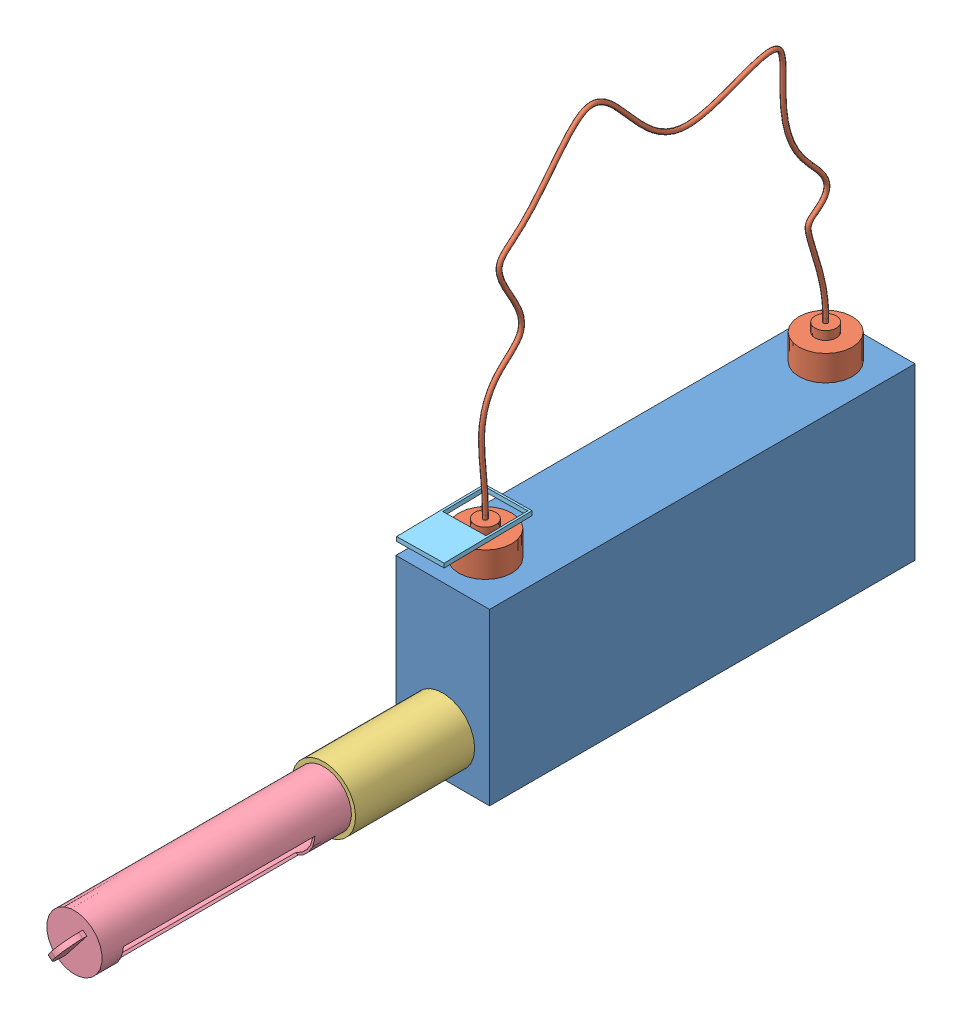
SolidWorks assembly lec44-path-mate-linear-coupler, configuration Default. Lengths in mm.
Overall size (55.88 307.6 486.58).
5 component instances, 5 part files, 22 mates.
Components (placement in the parent):
- Main Part_Path Mate-1: Main Part_Path Mate [Default] at (91.5285 149.8343 184.9571) size (55.88 101.6 254)
- Copy of Copy of Copy of Part3^lec44-path-mate-linear-coupler-1: Copy of Copy of Copy of Part3^lec44-path-mate-linear-coupler [Default] at (91.5285 200.6343 184.9571) x (1 0 0) z (0 1 0) size (31.75 234.95 254.26) (virtual)
- Part4^lec44-path-mate-linear-coupler-1: Part4^lec44-path-mate-linear-coupler [Default] at (67.487 132.6298 383.0215) x (0.322658 0.946515 0) z (0 0 1) size (38.1 38.1 228.6) (virtual)
- drawer_2-1: drawer_2 [Default] at (111.5159 108.7607 519.1401) x (-0.617072 -0.786907 0) z (0 0 1) size (33.02 33.02 241.3)
- Ring_2-1: Ring_2 [Default] at (91.5285 223.4943 286.5571) x (0.999879 0 -0.015556) z (0 1 0) size (27.94 53.34 2.54)
Mates (geometry in assembly coordinates):
- InPlace1: in place: plane of Main Part_Path Mate-1 through (123.2785 200.6343 57.9571) normal (0 1 0); plane of ? through (0 200.6343 0) normal (0 1 0); moOrthogonalPlaneRef_w of Main Part_Path Mate-1 through (123.2785 200.6343 57.9571) normal (0 1 0); plane of ? through (0 200.6343 0) normal (0 0 -1); plane of Main Part_Path Mate-1 through (123.2785 200.6343 57.9571) normal (0 1 0); line of ? through (-55 0 200.6343) axis (0 1 0); plane of Main Part_Path Mate-1 through (119.4685 200.6343 57.9571) normal (0 1 0); unknown of Copy of Copy of Copy of Part3^lec44-path-mate-linear-coupler-1
- Coincident1: coincident aligned: plane of ?; plane of ?
- Coincident2: coincident aligned: moOrthogonalPlaneRef_w of Main Part_Path Mate-1 through (91.5285 200.6343 184.9571) normal (0 0 -1); plane of Copy of Copy of Copy of Part3^lec36-path-mate-linear-coupler-1 through (91.5285 200.6343 184.9571) normal (0 0 -1)
- Coincident3: coincident anti-aligned: moOrthogonalPlaneRef_w of Main Part_Path Mate-1 through (91.5285 200.6343 184.9571) normal (-1 0 0); plane of Copy of Copy of Copy of Part3^lec36-path-mate-linear-coupler-1 through (91.5285 200.6343 184.9571) normal (1 0 0)
- InPlace2: in place: plane of Main Part_Path Mate-1 through (123.2785 200.6343 311.9571) normal (0 0 1); plane of ? through (0 0 311.9571) normal (0 0 1); plane of Main Part_Path Mate-1 through (123.2785 200.6343 311.9571) normal (0 0 1); plane of ? through (0 0 311.9571) normal (0 1 0); plane of Main Part_Path Mate-1 through (123.2785 200.6343 311.9571) normal (0 0 1); plane of ? through (0 0 311.9571) normal (1 0 0); plane of Main Part_Path Mate-1 through (119.4685 200.6343 311.9571) normal (0 0 1); unknown of ?
- Coincident1: coincident: plane of ?; plane of ?
- Coincident2: coincident aligned: moOrthogonalPlaneRef_w of Main Part_Path Mate-1 through (91.5285 149.8343 311.9571) normal (0 1 0); plane of Part4^lec36-path-mate-linear-coupler-1
- Coincident3: coincident anti-aligned: moOrthogonalPlaneRef_w of Main Part_Path Mate-1 through (91.5285 149.8343 311.9571) normal (-1 0 0); plane of Part4^lec36-path-mate-linear-coupler-1
- InPlace3: in place: plane of Main Part_Path Mate-1 through (123.2785 200.6343 311.9571) normal (0 0 1); plane of ? through (0 0 311.9571) normal (0 0 1); plane of Main Part_Path Mate-1 through (123.2785 200.6343 311.9571) normal (0 0 1); plane of ? through (0 0 311.9571) normal (0 1 0); plane of Main Part_Path Mate-1 through (123.2785 200.6343 311.9571) normal (0 0 1); plane of ? through (0 0 311.9571) normal (1 0 0); plane of Main Part_Path Mate-1 through (119.4685 200.6343 311.9571) normal (0 0 1); unknown of ?
- Coincident4: coincident: plane of ?; plane of ?
- Coincident5: coincident aligned: moOrthogonalPlaneRef_w of Main Part_Path Mate-1 through (91.5285 149.8343 311.9571) normal (0 1 0); plane of Part5^lec36-path-mate-linear-coupler-1
- Coincident6: coincident anti-aligned: moOrthogonalPlaneRef_w of Main Part_Path Mate-1 through (91.5285 149.8343 311.9571) normal (-1 0 0); plane of Part5^lec36-path-mate-linear-coupler-1
- InPlace4: in place: plane of Main Part_Path Mate-1 through (63.5885 149.8343 184.9571) normal (-1 0 0); plane of ? through (63.5885 0 0) normal (-1 0 0); plane of Main Part_Path Mate-1 through (63.5885 149.8343 184.9571) normal (-1 0 0); line of ? through (-55 63.5885 0) axis (0 0 1); plane of Main Part_Path Mate-1 through (63.5885 149.8343 184.9571) normal (-1 0 0); plane of ? through (63.5885 0 0) normal (0 0 1); plane of Main Part_Path Mate-1 through (63.5885 149.8343 184.9571) normal (-1 0 0); unknown of ?
- Coincident7: coincident aligned: plane of ?; plane of ?
- Coincident8: coincident aligned: moOrthogonalPlaneRef_w of Main Part_Path Mate-1 through (63.5885 149.8343 184.9571) normal (0 1 0); plane of Part6^lec36-path-mate-linear-coupler-1
- Coincident9: coincident anti-aligned: moOrthogonalPlaneRef_w of Main Part_Path Mate-1 through (63.5885 149.8343 184.9571) normal (0 0 -1); plane of Part6^lec36-path-mate-linear-coupler-1
- Concentric1: concentric aligned: cylinder of Main Part_Path Mate-1 through (91.5285 124.4343 4.0756) axis (0 0 1) radius 19.05; cylinder of Part4^lec36-path-mate-linear-coupler-1 through (91.5285 124.4343 154.4215) axis (0 0 1) radius 19.05
- Concentric2: concentric aligned: cylinder of Main Part_Path Mate-1 through (91.5285 124.4343 4.0756) axis (0 0 1) radius 19.05; cylinder of drawer_2-1 through (91.5285 124.4343 303.2401) axis (0 0 1) radius 16.51
- LimitDistance1: limit distance = 219.883 mm aligned: plane of drawer_2-1 through (91.5285 124.4343 531.8401) normal (0 0 1); plane of Main Part_Path Mate-1 through (119.4685 200.6343 311.9571) normal (0 0 1)
- LimitDistance2: limit distance = 71.0644 mm aligned: plane of Part4^lec36-path-mate-linear-coupler-1 through (91.5285 124.4343 383.0215) normal (0 0 1); plane of Main Part_Path Mate-1 through (119.4685 200.6343 311.9571) normal (0 0 1)
- PathMate1: path: point of Ring_2-1; curve of Copy of Copy of Copy of Part3^lec44-path-mate-linear-coupler-1
- Linear/Linear Coupler2: linear coupler = 76.2 : 25.4 mm: plane of drawer_2-1 through (91.5285 124.4343 531.8401) normal (0 0 1); cylinder of Part4^lec36-path-mate-linear-coupler-1 through (91.5285 124.4343 154.4215) axis (0 0 1) radius 19.05
